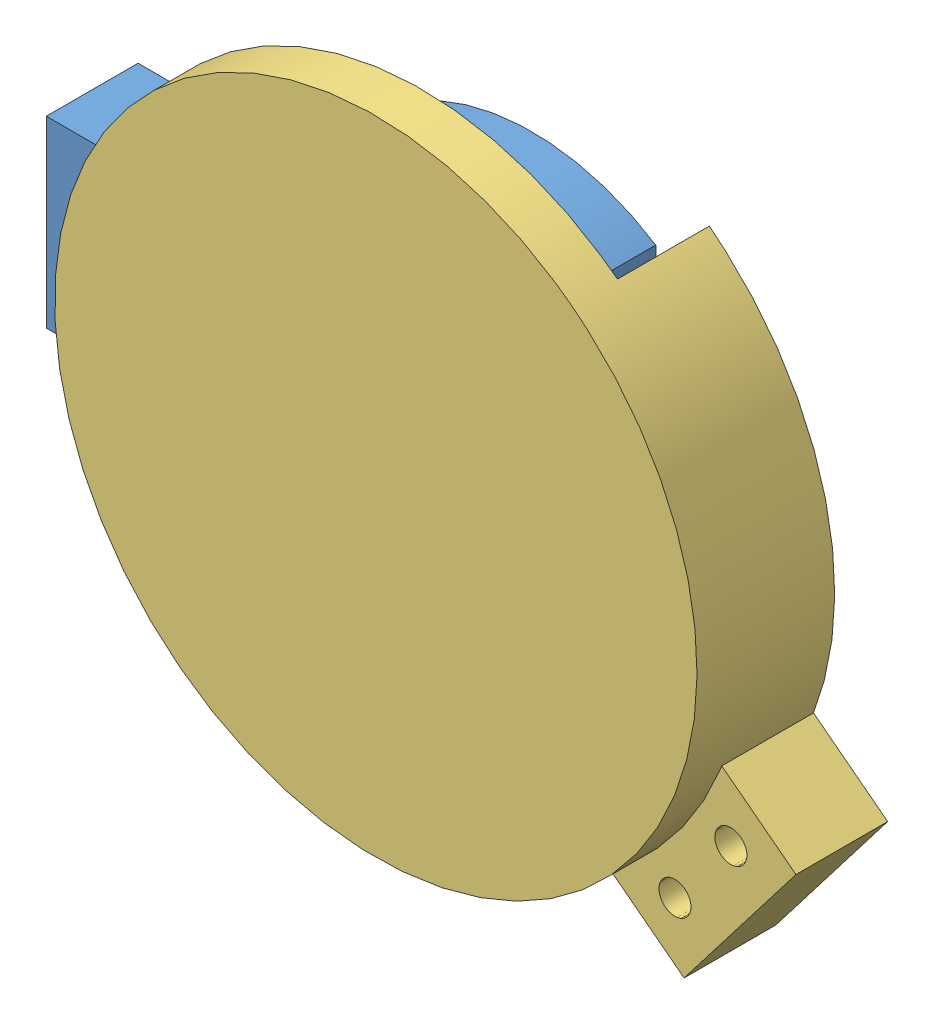
SolidWorks assembly Assem1, configuration Default. Lengths in mm.
Overall size (105.08 103.48 17).
3 component instances, 3 part files, 4 mates.
Components (placement in the parent):
- joint_upper_22mmID-1: joint_upper_22mmID [Default] at (25.8784 38.2633 49.528) size (67.79 50 10)
- 22mm_BALL BEARING-1: 22mm_BALL BEARING [5972K91] at (25.8784 38.2633 56.028) size (22 22 7)
- joint_lower_8mmOD_flat-1: joint_lower_8mmOD_flat [Default] at (25.8784 38.2633 52.528) x (0.609402 0.792861 0) z (0 0 1) size (70 78.74 15)
Mates (geometry in assembly coordinates):
- Coincident2: coincident aligned: plane of joint_upper_22mmID-1 through (25.8784 38.2633 59.528) normal (0 0 1); plane of 22mm_BALL BEARING-1 through (25.8784 48.9133 59.528) normal (0 0 1)
- Concentric2: concentric anti-aligned: cylinder of joint_upper_22mmID-1 through (25.8784 38.2633 59.528) axis (0 0 -1) radius 11; cylinder of 22mm_BALL BEARING-1 through (25.8784 38.2633 59.528) axis (0 0 1) radius 11
- Concentric3: concentric anti-aligned: cylinder of 22mm_BALL BEARING-1 through (25.8784 38.2633 59.528) axis (0 0 1) radius 4; cylinder of joint_lower_8mmOD_flat-1 through (25.8784 38.2633 59.528) axis (0 0 -1) radius 4.1
- Coincident3: coincident anti-aligned: plane of 22mm_BALL BEARING-1 through (25.8784 45.1039 59.528) normal (0 0 1); plane of joint_lower_8mmOD_flat-1 through (25.8784 38.2633 59.528) normal (0 0 -1)
